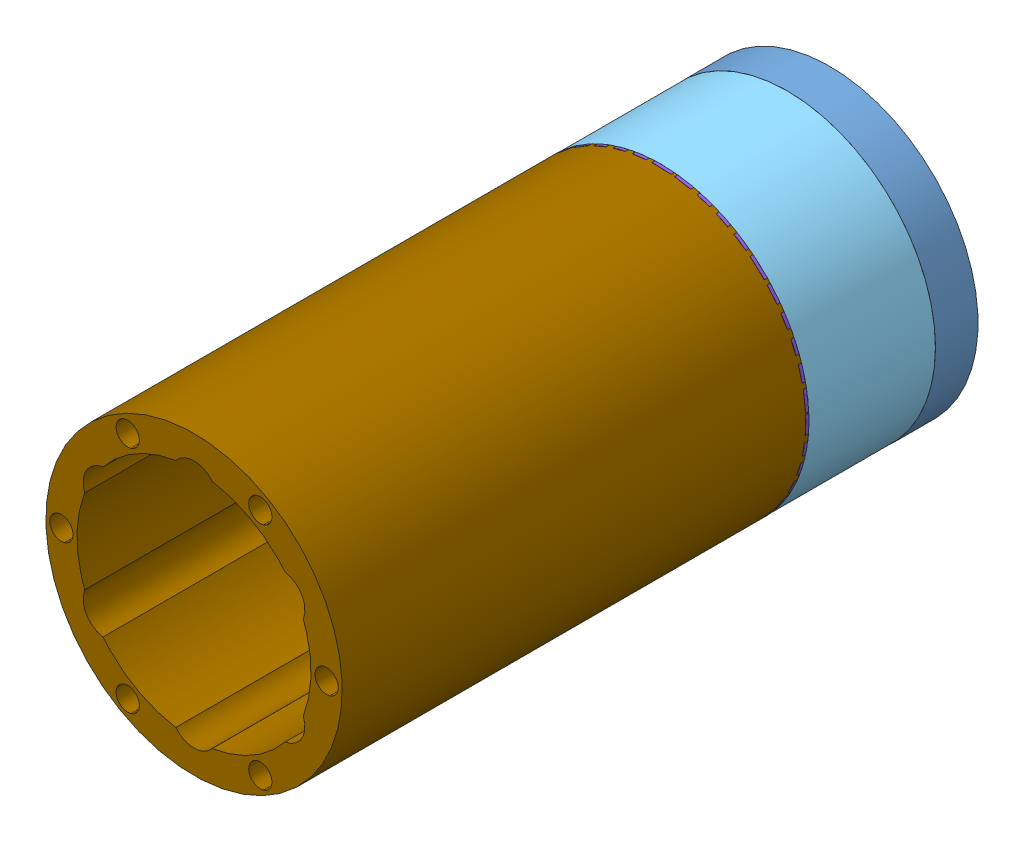
SolidWorks assembly FinalAssem, configuration Default. Lengths in mm.
Overall size (52.05 52.05 81.74).
9 component instances, 9 part files, 23 mates.
Components (placement in the parent):
- LightRetainer-1: LightRetainer [Default] at (3.8137 23.0152 32.609) size (38.1 38.1 5.48)
- Lense_CoverFinal-1: Lense_CoverFinal [Default] at (3.8137 23.0152 34.514) size (34.05 34.05 3.17)
- LenseCoverGasket-1: LenseCoverGasket [Default] at (3.8137 23.0152 34.1171) size (34.05 34.05 0.4)
- lense_10048_iss4_210512Final-1: lense_10048_iss4_210512Final [Default] at (3.8137 23.0152 38.9489) x (0.452055 0.89199 0) z (0 0 1) size (26.41 26.9 13.85)
- LenseHolderFinal-1: LenseHolderFinal [Default] at (3.8137 23.0152 52.4449) x (0 0 -1) z (1 0 0) size (16.26 38.1 38.1)
- LenseCoverGasketLenseHolder-1: LenseCoverGasketLenseHolder [Default] at (3.8137 23.0152 37.689) size (36 36 0.4)
- HeatsinkFinal-1: HeatsinkFinal [Default] at (3.8137 23.0152 59.4249) x (0 1 0) z (0 0 -1) size (33.99 33.99 5.08)
- InternalSealFrontFinal-1: InternalSealFrontFinal [Default] at (3.8137 23.0152 54.3449) size (38.1 38.1 0.4)
- TubeFinal-1: TubeFinal [Default] at (3.8137 23.0152 84.3449) x (0 0 -1) z (-0.5 -0.866025 0) size (60 38.1 38.1)
Mates (geometry in assembly coordinates):
- Coincident1: coincident anti-aligned: plane of LightRetainer-1 through (3.8137 23.0152 34.1171) normal (0 0 1); plane of LenseCoverGasket-1 through (3.8137 23.0152 34.1171) normal (0 0 -1)
- Concentric3: concentric aligned: cylinder of LightRetainer-1 through (11.5637 36.4386 37.689) axis (0 0 -1) radius 1.5; cylinder of LenseCoverGasket-1 through (11.5637 36.4386 34.514) axis (0 0 -1) radius 1.5
- Concentric4: concentric aligned: cylinder of LightRetainer-1 through (19.3137 23.0152 37.689) axis (0 0 -1) radius 1.5; cylinder of LenseCoverGasket-1 through (19.3137 23.0152 34.514) axis (0 0 -1) radius 1.5
- Concentric5: concentric anti-aligned: cylinder of LightRetainer-1 through (3.8137 23.0152 34.1171) axis (0 0 1) radius 17; cylinder of Lense_CoverFinal-1 through (3.8137 23.0152 37.689) axis (0 0 -1) radius 17.0257
- Concentric6: concentric aligned: cylinder of LightRetainer-1 through (11.5637 9.5918 37.689) axis (0 0 -1) radius 1.5; cylinder of Lense_CoverFinal-1 through (11.5637 9.5918 37.689) axis (0 0 -1) radius 1.5
- Coincident2: coincident anti-aligned: plane of Lense_CoverFinal-1 through (3.8137 23.0152 34.514) normal (0 0 -1); plane of LenseCoverGasket-1 through (3.8137 23.0152 34.514) normal (0 0 1)
- Concentric7: concentric aligned: cylinder of LightRetainer-1 through (3.8137 23.0152 37.689) axis (0 0 -1) radius 19.05; circle of lense_10048_iss4_210512-1
- Concentric8: concentric aligned: cylinder of LightRetainer-1 through (3.8137 23.0152 37.689) axis (0 0 -1) radius 19.05; cylinder of LenseCoverGasketLenseHolder-1 through (3.8137 23.0152 38.0858) axis (0 0 -1) radius 13.25
- Coincident4: coincident anti-aligned: cylinder of Lense_CoverFinal-1 through (19.3137 23.0152 37.689) axis (0 0 -1) radius 1.5; circle of LenseCoverGasketLenseHolder-1
- Coincident5: coincident anti-aligned: plane of Lense_CoverFinal-1 through (3.8137 23.0152 37.689) normal (0 0 1); plane of LenseCoverGasketLenseHolder-1 through (3.8137 23.0152 37.689) normal (0 0 -1)
- Concentric10: concentric anti-aligned: cylinder of LightRetainer-1 through (3.8137 23.0152 37.689) axis (0 0 -1) radius 19.05; cylinder of LenseHolderFinal-1 through (3.8137 23.0152 52.4449) axis (0 0 1) radius 19.05
- Concentric11: concentric aligned: cylinder of Lense_CoverFinal-1 through (19.3137 23.0152 37.689) axis (0 0 -1) radius 1.5; cylinder of LenseHolderFinal-1 through (19.3137 23.0152 58.1632) axis (0 0 -1) radius 1.35
- Coincident6: coincident anti-aligned: plane of LightRetainer-1 through (3.8137 23.0152 38.0858) normal (0 0 1); plane of LenseHolderFinal-1 through (3.8137 23.0152 38.0858) normal (0 0 -1)
- Coincident7: coincident anti-aligned: circle of lense_10048_iss4_210512Final-1; plane of LenseHolderFinal-1 through (3.8137 23.0152 38.9489) normal (0 0 -1)
- Concentric12: concentric aligned: cylinder of LenseHolderFinal-1 through (3.8137 23.0152 52.4449) axis (0 0 1) radius 19.05; cylinder of HeatsinkFinal-1 through (3.8137 23.0152 54.3449) axis (0 0 1) radius 16.995
- Coincident8: coincident anti-aligned: plane of LenseHolderFinal-1 through (3.8137 23.0152 54.3449) normal (0 0 1); plane of HeatsinkFinal-1 through (3.8137 23.0152 54.3449) normal (0 0 -1)
- Concentric14: concentric aligned: cylinder of LenseHolderFinal-1 through (3.8137 36.0152 44.3449) axis (0 0 1) radius 1.4958; cylinder of HeatsinkFinal-1 through (3.8137 36.0152 54.3449) axis (0 0 1) radius 1.5
- Coincident9: coincident anti-aligned: plane of LenseHolderFinal-1 through (3.8137 23.0152 54.3449) normal (0 0 1); plane of InternalSealFrontFinal-1 through (3.8137 23.0152 54.3449) normal (0 0 -1)
- Concentric15: concentric anti-aligned: cylinder of LenseHolderFinal-1 through (3.8137 23.0152 52.4449) axis (0 0 1) radius 19.05; cylinder of InternalSealFrontFinal-1 through (3.8137 23.0152 54.7417) axis (0 0 -1) radius 19.05
- Concentric20: concentric anti-aligned: cylinder of LenseHolderFinal-1 through (3.8137 23.0152 52.4449) axis (0 0 1) radius 19.05; cylinder of TubeFinal-1 through (3.8137 23.0152 84.3449) axis (0 0 -1) radius 19.05
- Concentric24: concentric anti-aligned: cylinder of HeatsinkFinal-1 through (-7.4446 29.5152 54.3449) axis (0 0 1) radius 1.5; cylinder of TubeFinal-1 through (-7.4446 29.5152 62.4249) axis (0 0 -1) radius 1.5
- Concentric25: concentric anti-aligned: cylinder of HeatsinkFinal-1 through (3.8137 10.0152 54.3449) axis (0 0 1) radius 1.5; cylinder of TubeFinal-1 through (3.8137 10.0152 62.4249) axis (0 0 -1) radius 1.5
- Coincident10: coincident anti-aligned: circle of InternalSealFrontFinal-1; circle of TubeFinal-1
